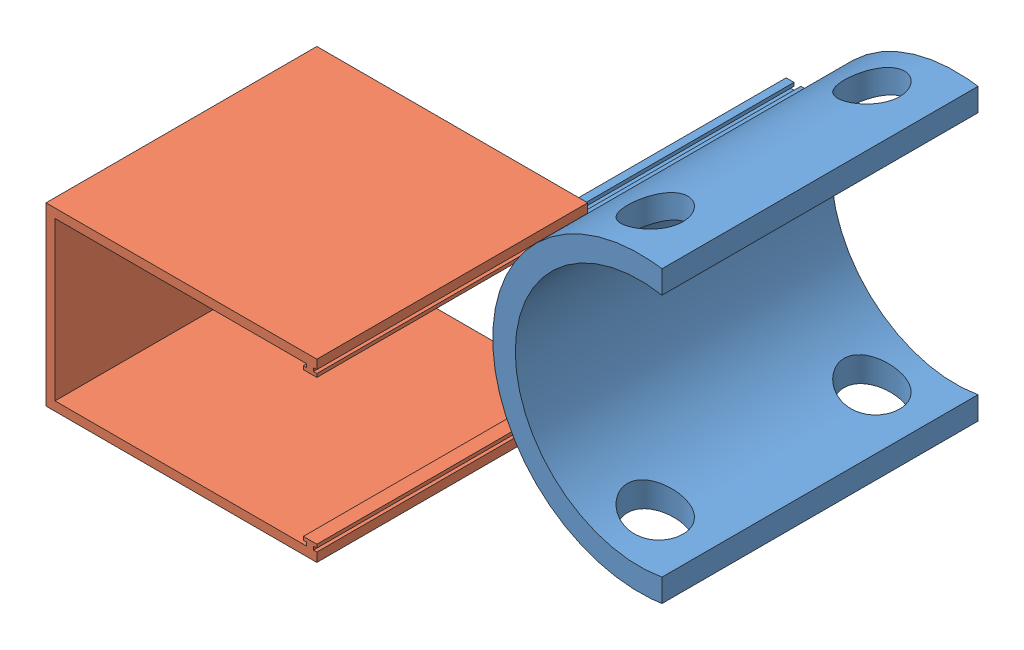
SolidWorks assembly V1 assemblage haut du bras, configuration Défaut. Lengths in mm.
Overall size (187 130 225.92).
2 component instances, 2 part files, 4 mates.
Components (placement in the parent):
- V1.1 differente haut du bras-2: V1.1 differente haut du bras [Défaut] at (0.1685 -2.877 70.0002) size (75 130 140)
- V1 capuchon electronique-2: V1 capuchon electronique [Défaut] at (-176.8315 36.123 295.9222) x (0 -1 0) z (1 0 0) size (78 120 120)
Mates (geometry in assembly coordinates):
- Parallèle3: parallel anti-aligned: plane of V1.1 differente haut du bras-2 through (-64.8315 32.123 200.0002) normal (0 0 1); plane of V1 capuchon electronique-2 through (-176.8315 36.123 175.9222) normal (0 0 -1)
- Coïncidente6: coincident anti-aligned: plane of V1.1 differente haut du bras-2 through (-56.8315 29.123 70.0001) normal (0 1 0); plane of V1 capuchon electronique-2 through (-56.8315 29.123 175.9222) normal (0 -1 0)
- Coïncidente7: coincident anti-aligned: plane of V1.1 differente haut du bras-2 through (-62.8315 29.123 70.0001) normal (1 0 0); plane of V1 capuchon electronique-2 through (-62.8315 30.623 175.9222) normal (-1 0 0)
- Coïncidente8: coincident anti-aligned: plane of V1.1 differente haut du bras-2 through (-62.8315 -34.877 70.0001) normal (1 0 0); plane of V1 capuchon electronique-2 through (-62.8315 -36.377 175.9222) normal (-1 0 0)
